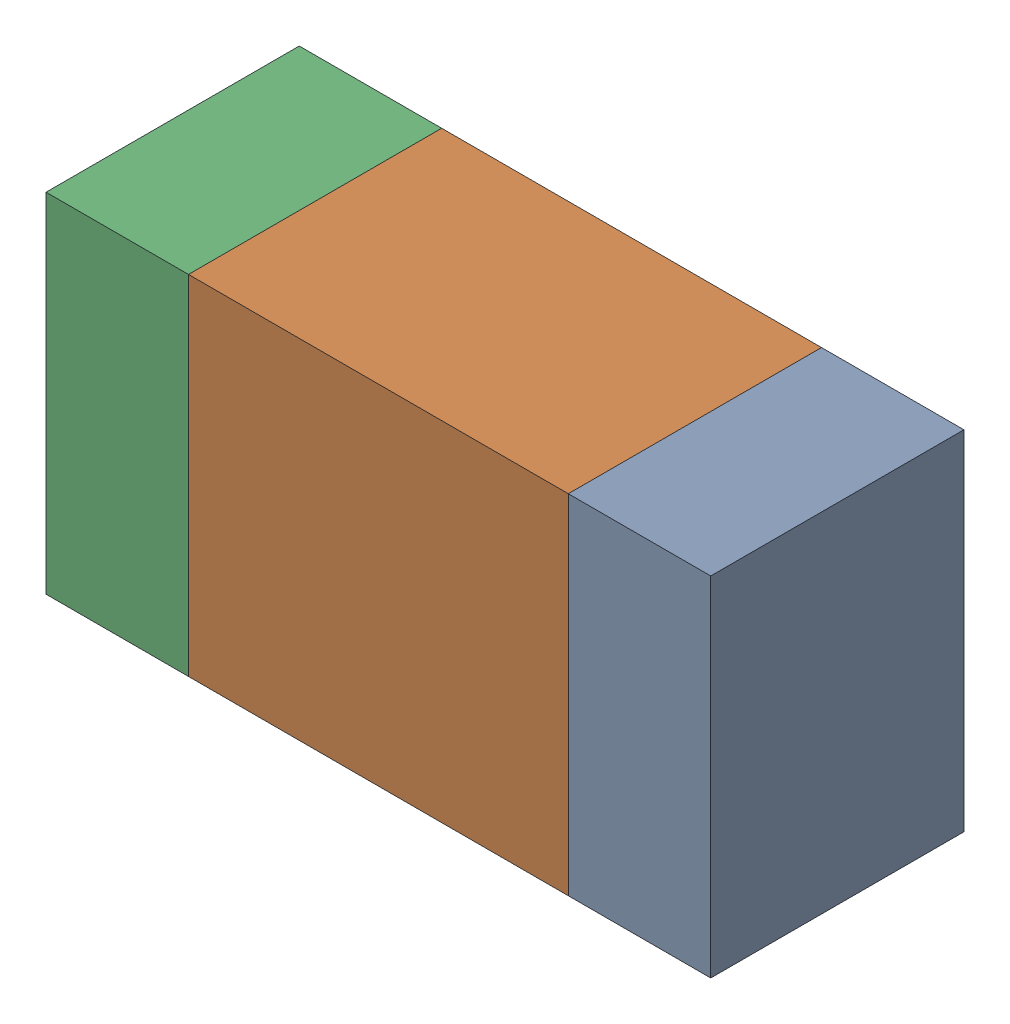
SolidWorks assembly R202PCB, configuration Default. Lengths in mm.
Overall size (1.05 0.55 0.4).
6 component instances, 2 part files, 0 mates.
Components (placement in the parent):
- 854785432-1: 854785432 [Default] at (95.1126 121.4001 0) size (0.22 0.55 0.4)
  - Extruded-1: Extruded [Default] at origin size (0.22 0.55 0.4)
- 854785568-1: 854785568 [Default] at (94.7001 121.4001 0) size (0.6 0.55 0.4)
  - Extruded_2-1: Extruded_2 [Default] at origin size (0.6 0.55 0.4)
- 854785432-2: 854785432 [Default] at (94.2876 121.4001 0) size (0.22 0.55 0.4)
  - Extruded-1: Extruded [Default] at origin size (0.22 0.55 0.4)
